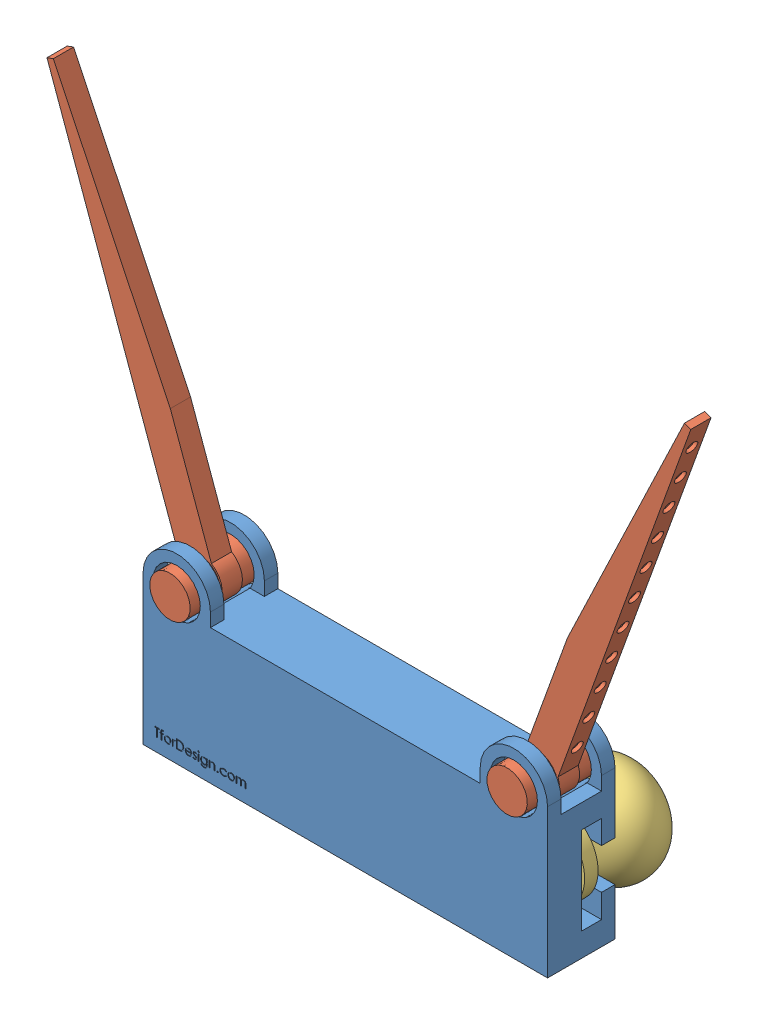
SolidWorks assembly lec34-symmetric-width, configuration Default. Lengths in mm.
Overall size (96.9 79.53 20.93).
4 component instances, 3 part files, 8 mates.
Components (placement in the parent):
- Main Body_15-1: Main Body_15 [Default] at (23.8141 35.8796 34.8255) size (60 27 10)
- Antenna-1: Antenna [Default] at (48.8141 47.8796 39.8255) x (0.33987 0.940472 0) z (-0.940472 0.33987 0) size (63.25 12 6.5)
- Knob-1: Knob [Default] at (47.8141 35.8796 39.3255) x (-0.995106 0.098809 0) z (-0.098809 -0.995106 0) size (14.93 14.43 14.93)
- Antenna-2: Antenna [Default] at (-1.1859 47.8796 39.8255) x (-0.33987 0.940472 0) z (0.940472 0.33987 0) size (63.25 12 6.5)
Mates (geometry in assembly coordinates):
- Concentric1: concentric anti-aligned: circle of Main Body_15-1; circle of Antenna-2
- Width1: width anti-aligned: plane of Main Body_15-1 through (53.8141 45.8796 36.8255) normal (0 0 1); plane of Antenna-2 through (53.8141 45.8796 42.8255) normal (0 0 -1); plane of Main Body_15-1 through (-1.1859 47.8796 38.3255) normal (0 0 -1); plane of Antenna-2 through (-1.1859 47.8796 41.3255) normal (0 0 1)
- Concentric2: concentric anti-aligned: circle of Main Body_15-1; circle of Antenna-1
- Width2: width anti-aligned: plane of Main Body_15-1 through (53.8141 45.8796 36.8255) normal (0 0 1); plane of Antenna-1 through (53.8141 45.8796 42.8255) normal (0 0 -1); plane of Main Body_15-1 through (48.8141 47.8796 38.3255) normal (0 0 -1); plane of Antenna-1 through (48.8141 47.8796 41.3255) normal (0 0 1)
- Symmetric1: symmetric aligned: plane of Main Body_15-1 through (23.8141 35.8796 34.8255) normal (1 0 0); plane of Antenna-2 through (51.1653 47.0299 39.8255) normal (0.940472 -0.33987 0); plane of Antenna-1 through (-3.5371 47.0299 39.8255) normal (-0.940472 -0.33987 0)
- Width3: width: cylinder of Main Body_15-1; plane of Knob-1 through (-6.1859 29.3796 34.8255) normal (0 1 0); cylinder of Main Body_15-1 through (47.8141 35.8796 25.5755) axis (0 0 -1) radius 6
- Width4: width anti-aligned: plane of Main Body_15-1 through (-6.1859 35.8796 36.8255) normal (0 0 1); plane of Knob-1 through (-6.1859 35.8796 39.8255) normal (0 0 -1); plane of Main Body_15-1 through (48.407 41.8502 37.3255) normal (0 0 -1); plane of Knob-1 through (47.8141 35.8796 39.3255) normal (0 0 1)
- Width5: width: plane of Main Body_15-1 through (-6.1859 45.8796 44.8255) normal (-1 0 0); plane of Knob-1 through (53.8141 45.8796 44.8255) normal (1 0 0); cylinder of Main Body_15-1 through (47.8141 35.8796 25.5755) axis (0 0 -1) radius 6
